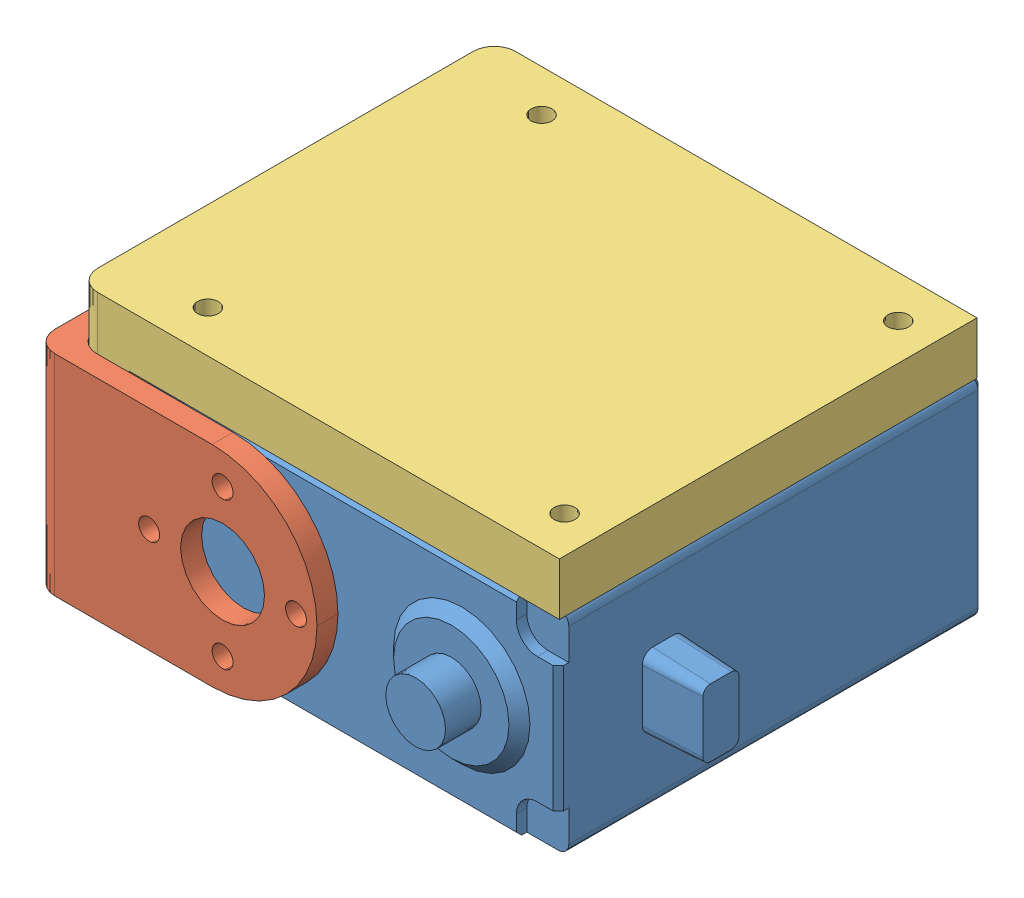
SolidWorks assembly moteur-complet, configuration Défaut. Lengths in mm.
Overall size (55.5 25 48.8).
11 component instances, 5 part files, 26 mates.
Components (placement in the parent):
- moteur-1: moteur [Défaut] at (-9.5825 -1.0731 48.8) size (45.5 20 48.8)
- moteur-support-fixe-1: moteur-support-fixe [Défaut] at (-5.7196 9.1116 15.94) x (1 0 0) z (0 -1 0) size (27.58 44 20)
- moteur_semelle-1: moteur_semelle [Défaut] at (-31.3007 -10.8884 28.8) x (-1 0 0) z (0 0 1) size (48 25 40)
- ecrou-h-1: ecrou-h [6007 HU M2] at (-27.7007 -5.8884 23.8) x (0 0.5 -0.866025) z (0 -0.866025 -0.5) size (4 1.6 4.62)
- ecrou-h-2: ecrou-h [6007 HU M2] at (-27.7007 -5.8884 33.8) x (0 -0.5 -0.866025) z (0 -0.866025 0.5) size (4 1.6 4.62)
- ecrou-h-3: ecrou-h [6007 HU M2] at (-27.7007 4.1116 33.8) x (0 -0.5 -0.866025) z (0 -0.866025 0.5) size (4 1.6 4.62)
- ecrou-h-4: ecrou-h [6007 HU M2] at (-27.7007 4.1116 23.8) x (0 -1 0) z (0 0 1) size (4 1.6 4.62)
- vis-chc-1: vis-chc [Vis CHC M2x6] at (-33.3007 -5.8884 33.8) x (0 -0.454411 0.890792) z (0 -0.890792 -0.454411) size (3.8 8 3.8)
- vis-chc-2: vis-chc [Vis CHC M2x6] at (-33.3007 4.1116 33.8) x (0 -0.381849 0.924225) z (0 -0.924225 -0.381849) size (3.8 8 3.8)
- vis-chc-3: vis-chc [Vis CHC M2x6] at (-33.3007 4.1116 23.8) x (0 -0.381849 0.924225) z (0 -0.924225 -0.381849) size (3.8 8 3.8)
- vis-chc-4: vis-chc [Vis CHC M2x6] at (-33.3007 -5.8884 23.8) x (0 -0.381849 0.924225) z (0 -0.924225 -0.381849) size (3.8 8 3.8)
Mates (geometry in assembly coordinates):
- Coaxiale12: concentric aligned: cylinder of moteur-1 through (-22.3007 -0.8884 43.8) axis (0 0 1) radius 0.79; cylinder of moteur-support-fixe-1 through (-22.3007 -0.8884 6.799) axis (0 0 1) radius 1
- Coaxiale13: concentric aligned: cylinder of moteur-1 through (-15.3007 -7.8884 43.8) axis (0 0 1) radius 0.79; cylinder of moteur-support-fixe-1 through (-15.3007 -7.8884 6.799) axis (0 0 1) radius 1
- Coïncidente2: coincident anti-aligned: plane of moteur-1 through (-9.5825 -1.0731 48.8) normal (0 0 1); plane of moteur-support-fixe-1 through (-29.3007 -10.8884 48.8) normal (0 0 -1)
- Coïncidente3: coincident anti-aligned: plane of moteur-support-fixe-1 through (-31.3007 -10.8884 10.8) normal (1 0 0); plane of moteur_semelle-1 through (-31.3007 14.1116 8.8) normal (-1 0 0)
- Coïncidente5: coincident anti-aligned: plane of moteur-1 through (-25.3007 9.1116 8.3) normal (0 1 0); plane of moteur_semelle-1 through (14.6993 9.1116 48.8) normal (0 -1 0)
- Coaxiale14: concentric anti-aligned: cylinder of moteur-support-fixe-1 through (-5.7186 -0.8884 28.8) axis (-1 0 0) radius 3; cylinder of moteur_semelle-1 through (-33.3007 -0.8884 28.8) axis (1 0 0) radius 2.9
- Coaxiale15: concentric anti-aligned: cylinder of moteur_semelle-1 through (14.7003 -5.8884 23.8) axis (-1 0 0) radius 1; cylinder of ecrou-h-m2-1 through (-29.3007 -5.8884 23.8) axis (1 0 0) radius 0.7835
- Parallèle2: parallel anti-aligned: plane of moteur_semelle-1 through (-29.3007 -7.9063 24.965) normal (0 1 0); plane of ecrou-h-m2-1 through (-29.3007 -7.8884 24.9547) normal (0 -1 0)
- Coïncidente9: coincident anti-aligned: plane of moteur_semelle-1 through (-29.3007 -10.8884 28.8) normal (1 0 0); plane of ecrou-h-m2-1 through (-29.3007 -3.8884 22.6453) normal (-1 0 0)
- Coaxiale16: concentric anti-aligned: cylinder of moteur_semelle-1 through (14.7003 4.1116 33.8) axis (-1 0 0) radius 1; cylinder of ecrou-h-m2-3 through (-29.3007 4.1116 33.8) axis (1 0 0) radius 0.7835
- Coaxiale17: concentric anti-aligned: cylinder of moteur_semelle-1 through (14.7003 4.1116 23.8) axis (-1 0 0) radius 1; cylinder of ecrou-h-m2-4 through (-29.3007 4.1116 23.8) axis (1 0 0) radius 0.7835
- Coaxiale18: concentric anti-aligned: cylinder of moteur_semelle-1 through (14.7003 -5.8884 33.8) axis (-1 0 0) radius 1; cylinder of ecrou-h-m2-2 through (-29.3007 -5.8884 33.8) axis (1 0 0) radius 0.7835
- Parallèle3: parallel anti-aligned: plane of moteur_semelle-1 through (-29.3007 -7.9063 34.965) normal (0 1 0); plane of ecrou-h-m2-2 through (-29.3007 -7.8884 34.9547) normal (0 -1 0)
- Coïncidente11: coincident anti-aligned: plane of moteur_semelle-1 through (-29.3007 -10.8884 28.8) normal (1 0 0); plane of ecrou-h-m2-2 through (-29.3007 -5.8884 31.4906) normal (-1 0 0)
- Parallèle4: parallel anti-aligned: plane of moteur_semelle-1 through (-29.3007 2.0937 24.965) normal (0 1 0); plane of ecrou-h-m2-4 through (-29.3007 2.1116 24.9547) normal (0 -1 0)
- Coïncidente13: coincident anti-aligned: plane of moteur_semelle-1 through (-29.3007 -10.8884 28.8) normal (1 0 0); plane of ecrou-h-m2-4 through (-29.3007 2.1116 22.6453) normal (-1 0 0)
- Parallèle5: parallel anti-aligned: plane of moteur_semelle-1 through (-29.3007 2.0937 34.965) normal (0 1 0); plane of ecrou-h-m2-3 through (-29.3007 2.1116 34.9547) normal (0 -1 0)
- Coïncidente15: coincident anti-aligned: plane of moteur_semelle-1 through (-29.3007 -10.8884 28.8) normal (1 0 0); plane of ecrou-h-m2-3 through (-29.3007 4.1116 31.4906) normal (-1 0 0)
- Coaxiale20: concentric aligned: cylinder of moteur-support-fixe-1 through (-5.7186 -5.8884 33.8) axis (-1 0 0) radius 1.5; cylinder of vis-chc-m2x5-1 through (-27.3007 -5.8884 33.8) axis (-1 0 0) radius 1
- Coaxiale21: concentric aligned: cylinder of moteur-support-fixe-1 through (-5.7186 -5.8884 23.8) axis (-1 0 0) radius 1.5; cylinder of vis-chc-m2x5-4 through (-27.3007 -5.8884 23.8) axis (-1 0 0) radius 1
- Coaxiale22: concentric aligned: cylinder of moteur-support-fixe-1 through (-5.7186 4.1116 23.8) axis (-1 0 0) radius 1.5; cylinder of vis-chc-m2x5-3 through (-27.3007 4.1116 23.8) axis (-1 0 0) radius 1
- Coaxiale23: concentric aligned: cylinder of moteur-support-fixe-1 through (-5.7186 4.1116 33.8) axis (-1 0 0) radius 1.5; cylinder of vis-chc-m2x5-2 through (-27.3007 4.1116 33.8) axis (-1 0 0) radius 1
- Coïncidente18: coincident anti-aligned: plane of moteur-support-fixe-1 through (-33.3007 -10.8884 48.8) normal (-1 0 0); plane of vis-chc-m2x5-2 through (-33.3007 4.1116 33.8) normal (1 0 0)
- Coïncidente19: coincident anti-aligned: plane of moteur-support-fixe-1 through (-33.3007 -10.8884 48.8) normal (-1 0 0); plane of vis-chc-m2x5-3 through (-33.3007 4.1116 23.8) normal (1 0 0)
- Coïncidente20: coincident anti-aligned: plane of moteur-support-fixe-1 through (-33.3007 -10.8884 48.8) normal (-1 0 0); plane of vis-chc-m2x5-1 through (-33.3007 -5.8884 33.8) normal (1 0 0)
- Coïncidente21: coincident anti-aligned: plane of moteur-support-fixe-1 through (-33.3007 -10.8884 48.8) normal (-1 0 0); plane of vis-chc-m2x5-4 through (-33.3007 -5.8884 23.8) normal (1 0 0)
